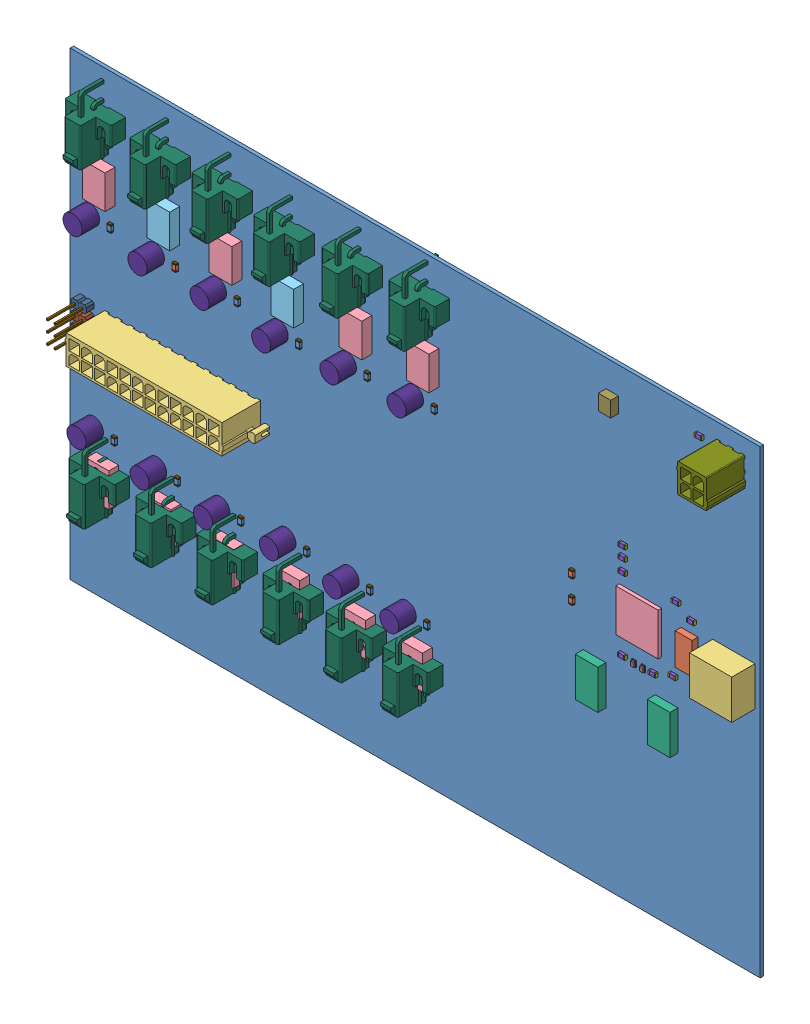
SolidWorks assembly PCBnew, configuration Default. Lengths in mm.
Overall size (228.6 152.53 16.3).
344 component instances, 22 part files, 0 mates.
Components (placement in the parent):
- Board-1: Board [Default] at (0 0 -1.1151) size (228.6 152.53 1.13)
- FTDI-1: FTDI [Default] at origin size (5.6 10.5 1.95)
  - 365783072-1: 365783072 [Default] at (230.632 107.696 0.0627) size (5.6 10.5 1.95)
    - Extruded-1: Extruded [Default] at origin size (5.6 10.5 1.95)
- USB1-1: USB1 [Default] at origin size (14 13 7.7)
  - 365780640-1: 365780640 [Default] at (245.268 108.204 0.0127) size (14 13 7.7)
    - Extruded_1-1: Extruded_1 [Default] at origin size (14 13 7.7)
- U4_Motor_11-1: U4_Motor_11 [Default] at origin size (7.5 11.1 3.3)
  - 365782816-1: 365782816 [Default] at (36.576 145.669 0.1127) size (7.5 11.1 3.3)
    - Extruded_2-1: Extruded_2 [Default] at origin size (7.5 11.1 3.3)
- U4_Motor_10-1: U4_Motor_10 [Default] at origin size (7.5 11.1 3.3)
  - 365782944-1: 365782944 [Default] at (58.039 145.161 0.1127) size (7.5 11.1 3.3)
    - Extruded_3-1: Extruded_3 [Default] at origin size (7.5 11.1 3.3)
- U4_Motor_9-1: U4_Motor_9 [Default] at origin size (7.5 11.1 3.3)
  - 365782816-1: 365782816 [Default] at (78.613 145.542 0.1127) size (7.5 11.1 3.3)
    - Extruded_2-1: Extruded_2 [Default] at origin size (7.5 11.1 3.3)
- U4_Motor_8-1: U4_Motor_8 [Default] at origin size (7.5 11.1 3.3)
  - 365782944-1: 365782944 [Default] at (99.06 143.51 0.1127) size (7.5 11.1 3.3)
    - Extruded_3-1: Extruded_3 [Default] at origin size (7.5 11.1 3.3)
- U4_Motor_7-1: U4_Motor_7 [Default] at origin size (7.5 11.1 3.3)
  - 365782816-1: 365782816 [Default] at (121.666 145.669 0.1127) size (7.5 11.1 3.3)
    - Extruded_2-1: Extruded_2 [Default] at origin size (7.5 11.1 3.3)
- U4_Motor_6-1: U4_Motor_6 [Default] at origin size (7.5 11.1 3.3)
  - 365782816-1: 365782816 [Default] at (143.891 147.32 0.1127) size (7.5 11.1 3.3)
    - Extruded_2-1: Extruded_2 [Default] at origin size (7.5 11.1 3.3)
- U4_Motor_5-1: U4_Motor_5 [Default] at origin size (7.5 11.1 3.3)
  - 365782816-1: 365782816 [Default] at (37.846 60.833 0.1127) size (7.5 11.1 3.3)
    - Extruded_2-1: Extruded_2 [Default] at origin size (7.5 11.1 3.3)
- U4_Motor_4-1: U4_Motor_4 [Default] at origin size (7.5 11.1 3.3)
  - 365782816-1: 365782816 [Default] at (58.42 59.944 0.1127) size (7.5 11.1 3.3)
    - Extruded_2-1: Extruded_2 [Default] at origin size (7.5 11.1 3.3)
- U4_Motor_3-1: U4_Motor_3 [Default] at origin size (7.5 11.1 3.3)
  - 365782816-1: 365782816 [Default] at (79.248 58.928 0.1127) size (7.5 11.1 3.3)
    - Extruded_2-1: Extruded_2 [Default] at origin size (7.5 11.1 3.3)
- U4_Motor_2-1: U4_Motor_2 [Default] at origin size (7.5 11.1 3.3)
  - 365782816-1: 365782816 [Default] at (101.092 60.96 0.1127) size (7.5 11.1 3.3)
    - Extruded_2-1: Extruded_2 [Default] at origin size (7.5 11.1 3.3)
- U4_Motor_1-1: U4_Motor_1 [Default] at origin size (7.5 11.1 3.3)
  - 365782816-1: 365782816 [Default] at (122.936 60.452 0.1127) size (7.5 11.1 3.3)
    - Extruded_2-1: Extruded_2 [Default] at origin size (7.5 11.1 3.3)
- U4_Motor_0-1: U4_Motor_0 [Default] at origin size (7.5 11.1 3.3)
  - 365782816-1: 365782816 [Default] at (141.732 60.452 0.1127) size (7.5 11.1 3.3)
    - Extruded_2-1: Extruded_2 [Default] at origin size (7.5 11.1 3.3)
- U3-1: U3 [Default] at origin size (7.5 13 2.65)
  - 365782560-1: 365782560 [Default] at (199.136 83.82 0.0127) size (7.5 13 2.65)
    - Extruded_4-1: Extruded_4 [Default] at origin size (7.5 13 2.65)
- U2-1: U2 [Default] at origin size (7.5 13 2.65)
  - 365782560-1: 365782560 [Default] at (223.012 82.804 0.0127) size (7.5 13 2.65)
    - Extruded_4-1: Extruded_4 [Default] at origin size (7.5 13 2.65)
- R5-1: R5 [Default] at origin size (2.38 1.3 0.85)
  - 365781408-1: 365781408 [Default] at (235.188 171.196 0.0127) size (0.38 1.3 0.85)
    - Extruded_5-1: Extruded_5 [Default] at origin size (0.38 1.3 0.85)
  - 365781536-1: 365781536 [Default] at (234.188 171.196 0.0127) size (2.2 1.27 0.85)
    - Extruded_6-1: Extruded_6 [Default] at origin size (2.2 1.27 0.85)
  - 365781408-2: 365781408 [Default] at (233.188 171.196 0.0127) size (0.38 1.3 0.85)
    - Extruded_5-1: Extruded_5 [Default] at origin size (0.38 1.3 0.85)
- R4-1: R4 [Default] at origin size (2.38 1.3 0.85)
  - 365781408-1: 365781408 [Default] at (219.948 95.504 0.0127) size (0.38 1.3 0.85)
    - Extruded_5-1: Extruded_5 [Default] at origin size (0.38 1.3 0.85)
  - 365781536-1: 365781536 [Default] at (218.948 95.504 0.0127) size (2.2 1.27 0.85)
    - Extruded_6-1: Extruded_6 [Default] at origin size (2.2 1.27 0.85)
  - 365781408-2: 365781408 [Default] at (217.948 95.504 0.0127) size (0.38 1.3 0.85)
    - Extruded_5-1: Extruded_5 [Default] at origin size (0.38 1.3 0.85)
- R3-1: R3 [Default] at origin size (2.38 1.3 0.85)
  - 365781408-1: 365781408 [Default] at (209.788 95.504 0.0127) size (0.38 1.3 0.85)
    - Extruded_5-1: Extruded_5 [Default] at origin size (0.38 1.3 0.85)
  - 365781536-1: 365781536 [Default] at (208.788 95.504 0.0127) size (2.2 1.27 0.85)
    - Extruded_6-1: Extruded_6 [Default] at origin size (2.2 1.27 0.85)
  - 365781408-2: 365781408 [Default] at (207.788 95.504 0.0127) size (0.38 1.3 0.85)
    - Extruded_5-1: Extruded_5 [Default] at origin size (0.38 1.3 0.85)
- R2-1: R2 [Default] at origin size (2.38 1.3 0.85)
  - 365781408-1: 365781408 [Default] at (226.552 98.044 0.0127) size (0.38 1.3 0.85)
    - Extruded_5-1: Extruded_5 [Default] at origin size (0.38 1.3 0.85)
  - 365781536-1: 365781536 [Default] at (225.552 98.044 0.0127) size (2.2 1.27 0.85)
    - Extruded_6-1: Extruded_6 [Default] at origin size (2.2 1.27 0.85)
  - 365781408-2: 365781408 [Default] at (224.552 98.044 0.0127) size (0.38 1.3 0.85)
    - Extruded_5-1: Extruded_5 [Default] at origin size (0.38 1.3 0.85)
- R1-1: R1 [Default] at origin size (2.38 1.3 0.85)
  - 365781408-1: 365781408 [Default] at (227.568 119.888 0.0127) size (0.38 1.3 0.85)
    - Extruded_5-1: Extruded_5 [Default] at origin size (0.38 1.3 0.85)
  - 365781536-1: 365781536 [Default] at (226.568 119.888 0.0127) size (2.2 1.27 0.85)
    - Extruded_6-1: Extruded_6 [Default] at origin size (2.2 1.27 0.85)
  - 365781408-2: 365781408 [Default] at (225.568 119.888 0.0127) size (0.38 1.3 0.85)
    - Extruded_5-1: Extruded_5 [Default] at origin size (0.38 1.3 0.85)
- P3-1: P3 [Default] at origin size (5.08 2.54 14.73)
  - 365780768-1: 365780768 [Default] at (29.464 107.823 -3.0353) size (0.51 0.51 14.73)
    - Extruded_7-1: Extruded_7 [Default] at origin size (0.51 0.51 14.73)
  - 365780768-2: 365780768 [Default] at (32.004 107.823 -3.0353) size (0.51 0.51 14.73)
    - Extruded_7-1: Extruded_7 [Default] at origin size (0.51 0.51 14.73)
  - 365781152-1: 365781152 [Default] at (29.464 107.823 0.0127) size (2.54 2.54 2.54)
    - Extruded_8-1: Extruded_8 [Default] at origin size (2.54 2.54 2.54)
  - 365781152-2: 365781152 [Default] at (32.004 107.823 0.0127) size (2.54 2.54 2.54)
    - Extruded_8-1: Extruded_8 [Default] at origin size (2.54 2.54 2.54)
- P2-1: P2 [Default] at origin size (5.08 2.54 14.73)
  - 365780768-1: 365780768 [Default] at (32.004 104.267 -3.0353) size (0.51 0.51 14.73)
    - Extruded_7-1: Extruded_7 [Default] at origin size (0.51 0.51 14.73)
  - 365780768-2: 365780768 [Default] at (29.464 104.267 -3.0353) size (0.51 0.51 14.73)
    - Extruded_7-1: Extruded_7 [Default] at origin size (0.51 0.51 14.73)
  - 365781024-1: 365781024 [Default] at (32.004 104.267 0.0127) size (2.54 2.54 2.54)
    - Extruded_9-1: Extruded_9 [Default] at origin size (2.54 2.54 2.54)
  - 365781024-2: 365781024 [Default] at (29.464 104.267 0.0127) size (2.54 2.54 2.54)
    - Extruded_9-1: Extruded_9 [Default] at origin size (2.54 2.54 2.54)
- P1-1: P1 [Default] at origin size (5.08 2.54 14.73)
  - 365780768-1: 365780768 [Default] at (32.004 100.711 -3.0353) size (0.51 0.51 14.73)
    - Extruded_7-1: Extruded_7 [Default] at origin size (0.51 0.51 14.73)
  - 365780768-2: 365780768 [Default] at (29.464 100.711 -3.0353) size (0.51 0.51 14.73)
    - Extruded_7-1: Extruded_7 [Default] at origin size (0.51 0.51 14.73)
  - 365781024-1: 365781024 [Default] at (32.004 100.711 0.0127) size (2.54 2.54 2.54)
    - Extruded_9-1: Extruded_9 [Default] at origin size (2.54 2.54 2.54)
  - 365781024-2: 365781024 [Default] at (29.464 100.711 0.0127) size (2.54 2.54 2.54)
    - Extruded_9-1: Extruded_9 [Default] at origin size (2.54 2.54 2.54)
- NPP-301-1: NPP-301 [Default] at origin size (4.1 5.1 2.55)
  - 365782432-1: 365782432 [Default] at (205.232 166.624 0.2627) size (4.1 5.1 2.55)
    - Extruded_10-1: Extruded_10 [Default] at origin size (4.1 5.1 2.55)
- LED2-1: LED2 [Default] at origin size (1.25 2 0.8)
  - 365782304-1: 365782304 [Default] at (215.392 94.9835 0.0127) size (1.15 1.38 0.8)
    - Extruded_11-1: Extruded_11 [Default] at origin size (1.15 1.38 0.8)
  - 365782176-1: 365782176 [Default] at (215.392 94.996 0.0127) size (1.25 2 0.3)
    - Extruded_12-1: Extruded_12 [Default] at origin size (1.25 2 0.3)
- LED1-1: LED1 [Default] at origin size (1.25 2 0.8)
  - 365782304-1: 365782304 [Default] at (212.344 94.9835 0.0127) size (1.15 1.38 0.8)
    - Extruded_11-1: Extruded_11 [Default] at origin size (1.15 1.38 0.8)
  - 365782176-1: 365782176 [Default] at (212.344 94.996 0.0127) size (1.25 2 0.3)
    - Extruded_12-1: Extruded_12 [Default] at origin size (1.25 2 0.3)
- Con2_Motor_11-1: Con2_Motor_11 [Default] at origin size (15.4 19.9 14.9)
  - 039291027-1: 039291027 [Default] at (36.0931 154.4521 0.0127) x (1 0 0) z (0 -1 0) size (15.4 14.9 19.9)
    - Open CASCADE STEP translator 6.2 19.29.1.1-1: Open CASCADE STEP translator 6.2 19.29.1.1 [Default] at origin size (15.4 14.9 19.9)
- Con2_Motor_10-1: Con2_Motor_10 [Default] at origin size (15.4 19.9 14.9)
  - 039291027-1: 039291027 [Default] at (57.5561 153.9441 0.0127) x (1 0 0) z (0 -1 0) size (15.4 14.9 19.9)
    - Open CASCADE STEP translator 6.2 19.29.1.1-1: Open CASCADE STEP translator 6.2 19.29.1.1 [Default] at origin size (15.4 14.9 19.9)
- Con2_Motor_9-1: Con2_Motor_9 [Default] at origin size (15.4 19.9 14.9)
  - 039291027-1: 039291027 [Default] at (78.1301 154.3251 0.0127) x (1 0 0) z (0 -1 0) size (15.4 14.9 19.9)
    - Open CASCADE STEP translator 6.2 19.29.1.1-1: Open CASCADE STEP translator 6.2 19.29.1.1 [Default] at origin size (15.4 14.9 19.9)
- Con2_Motor_8-1: Con2_Motor_8 [Default] at origin size (15.4 19.9 14.9)
  - 039291027-1: 039291027 [Default] at (98.5771 152.2931 0.0127) x (1 0 0) z (0 -1 0) size (15.4 14.9 19.9)
    - Open CASCADE STEP translator 6.2 19.29.1.1-1: Open CASCADE STEP translator 6.2 19.29.1.1 [Default] at origin size (15.4 14.9 19.9)
- Con2_Motor_7-1: Con2_Motor_7 [Default] at origin size (15.4 19.9 14.9)
  - 039291027-1: 039291027 [Default] at (121.1831 154.4521 0.0127) x (1 0 0) z (0 -1 0) size (15.4 14.9 19.9)
    - Open CASCADE STEP translator 6.2 19.29.1.1-1: Open CASCADE STEP translator 6.2 19.29.1.1 [Default] at origin size (15.4 14.9 19.9)
- Con2_Motor_6-1: Con2_Motor_6 [Default] at origin size (15.4 19.9 14.9)
  - 039291027-1: 039291027 [Default] at (143.4081 156.1031 0.0127) x (1 0 0) z (0 -1 0) size (15.4 14.9 19.9)
    - Open CASCADE STEP translator 6.2 19.29.1.1-1: Open CASCADE STEP translator 6.2 19.29.1.1 [Default] at origin size (15.4 14.9 19.9)
- Con2_Motor_5-1: Con2_Motor_5 [Default] at origin size (15.4 19.9 14.9)
  - 039291027-1: 039291027 [Default] at (37.3631 52.0499 0.0127) x (1 0 0) z (0 -1 0) size (15.4 14.9 19.9)
    - Open CASCADE STEP translator 6.2 19.29.1.1-1: Open CASCADE STEP translator 6.2 19.29.1.1 [Default] at origin size (15.4 14.9 19.9)
- Con2_Motor_4-1: Con2_Motor_4 [Default] at origin size (15.4 19.9 14.9)
  - 039291027-1: 039291027 [Default] at (59.4611 52.0499 0.0127) x (1 0 0) z (0 -1 0) size (15.4 14.9 19.9)
    - Open CASCADE STEP translator 6.2 19.29.1.1-1: Open CASCADE STEP translator 6.2 19.29.1.1 [Default] at origin size (15.4 14.9 19.9)
- Con2_Motor_3-1: Con2_Motor_3 [Default] at origin size (15.4 19.9 14.9)
  - 039291027-1: 039291027 [Default] at (79.7811 51.5419 0.0127) x (1 0 0) z (0 -1 0) size (15.4 14.9 19.9)
    - Open CASCADE STEP translator 6.2 19.29.1.1-1: Open CASCADE STEP translator 6.2 19.29.1.1 [Default] at origin size (15.4 14.9 19.9)
- Con2_Motor_2-1: Con2_Motor_2 [Default] at origin size (15.4 19.9 14.9)
  - 039291027-1: 039291027 [Default] at (101.6251 51.0339 0.0127) x (1 0 0) z (0 -1 0) size (15.4 14.9 19.9)
    - Open CASCADE STEP translator 6.2 19.29.1.1-1: Open CASCADE STEP translator 6.2 19.29.1.1 [Default] at origin size (15.4 14.9 19.9)
- Con2_Motor_1-1: Con2_Motor_1 [Default] at origin size (15.4 19.9 14.9)
  - 039291027-1: 039291027 [Default] at (122.4531 50.5259 0.0127) x (1 0 0) z (0 -1 0) size (15.4 14.9 19.9)
    - Open CASCADE STEP translator 6.2 19.29.1.1-1: Open CASCADE STEP translator 6.2 19.29.1.1 [Default] at origin size (15.4 14.9 19.9)
- Con2_Motor_0-1: Con2_Motor_0 [Default] at origin size (15.4 19.9 14.9)
  - 039291027-1: 039291027 [Default] at (141.2491 50.0179 0.0127) x (1 0 0) z (0 -1 0) size (15.4 14.9 19.9)
    - Open CASCADE STEP translator 6.2 19.29.1.1-1: Open CASCADE STEP translator 6.2 19.29.1.1 [Default] at origin size (15.4 14.9 19.9)
- Con1-1: Con1 [Default] at origin size (10.4 11 16.3)
  - 039281043-1: 039281043 [Default] at (244.214 168.047 0.0127) x (1 0 0) z (0 -1 0) size (10.4 16.3 11)
- C10_Motor_11-1: C10_Motor_11 [Default] at origin size (6.32 6.32 5.8)
  - 365780896-1: 365780896 [Default] at (32.004 133.477 0.0127) size (6.32 6.32 5.8)
    - Extruded_13-1: Extruded_13 [Default] at origin size (6.32 6.32 5.8)
- C10_Motor_10-1: C10_Motor_10 [Default] at origin size (6.32 6.32 5.8)
  - 365780896-1: 365780896 [Default] at (53.467 132.969 0.0127) size (6.32 6.32 5.8)
    - Extruded_13-1: Extruded_13 [Default] at origin size (6.32 6.32 5.8)
- C10_Motor_9-1: C10_Motor_9 [Default] at origin size (6.32 6.32 5.8)
  - 365780896-1: 365780896 [Default] at (74.041 133.35 0.0127) size (6.32 6.32 5.8)
    - Extruded_13-1: Extruded_13 [Default] at origin size (6.32 6.32 5.8)
- C10_Motor_8-1: C10_Motor_8 [Default] at origin size (6.32 6.32 5.8)
  - 365780896-1: 365780896 [Default] at (94.488 131.318 0.0127) size (6.32 6.32 5.8)
    - Extruded_13-1: Extruded_13 [Default] at origin size (6.32 6.32 5.8)
- C10_Motor_7-1: C10_Motor_7 [Default] at origin size (6.32 6.32 5.8)
  - 365780896-1: 365780896 [Default] at (117.094 133.477 0.0127) size (6.32 6.32 5.8)
    - Extruded_13-1: Extruded_13 [Default] at origin size (6.32 6.32 5.8)
- C10_Motor_6-1: C10_Motor_6 [Default] at origin size (6.32 6.32 5.8)
  - 365780896-1: 365780896 [Default] at (139.319 135.128 0.0127) size (6.32 6.32 5.8)
    - Extruded_13-1: Extruded_13 [Default] at origin size (6.32 6.32 5.8)
- C10_Motor_5-1: C10_Motor_5 [Default] at origin size (6.32 6.32 5.8)
  - 365780896-1: 365780896 [Default] at (33.274 73.025 0.0127) size (6.32 6.32 5.8)
    - Extruded_13-1: Extruded_13 [Default] at origin size (6.32 6.32 5.8)
- C10_Motor_4-1: C10_Motor_4 [Default] at origin size (6.32 6.32 5.8)
  - 365780896-1: 365780896 [Default] at (54.229 71.882 0.0127) size (6.32 6.32 5.8)
    - Extruded_13-1: Extruded_13 [Default] at origin size (6.32 6.32 5.8)
- C10_Motor_3-1: C10_Motor_3 [Default] at origin size (6.32 6.32 5.8)
  - 365780896-1: 365780896 [Default] at (75.184 70.993 0.0127) size (6.32 6.32 5.8)
    - Extruded_13-1: Extruded_13 [Default] at origin size (6.32 6.32 5.8)
- C10_Motor_2-1: C10_Motor_2 [Default] at origin size (6.32 6.32 5.8)
  - 365780896-1: 365780896 [Default] at (97.028 73.025 0.0127) size (6.32 6.32 5.8)
    - Extruded_13-1: Extruded_13 [Default] at origin size (6.32 6.32 5.8)
- C10_Motor_1-1: C10_Motor_1 [Default] at origin size (6.32 6.32 5.8)
  - 365780896-1: 365780896 [Default] at (117.983 72.517 0.0127) size (6.32 6.32 5.8)
    - Extruded_13-1: Extruded_13 [Default] at origin size (6.32 6.32 5.8)
- C10_Motor_0-1: C10_Motor_0 [Default] at origin size (6.32 6.32 5.8)
  - 365780896-1: 365780896 [Default] at (136.906 72.009 0.0127) size (6.32 6.32 5.8)
    - Extruded_13-1: Extruded_13 [Default] at origin size (6.32 6.32 5.8)
- C9_Motor_11-1: C9_Motor_11 [Default] at origin size (1.3 2.38 0.85)
  - 365781792-1: 365781792 [Default] at (39.116 134.477 0.0127) size (1.3 0.38 0.85)
    - Extruded_14-1: Extruded_14 [Default] at origin size (1.3 0.38 0.85)
  - 365782048-1: 365782048 [Default] at (39.116 133.477 0.0127) size (1.27 2.2 0.85)
    - Extruded_15-1: Extruded_15 [Default] at origin size (1.27 2.2 0.85)
  - 365781792-2: 365781792 [Default] at (39.116 132.477 0.0127) size (1.3 0.38 0.85)
    - Extruded_14-1: Extruded_14 [Default] at origin size (1.3 0.38 0.85)
- C9_Motor_10-1: C9_Motor_10 [Default] at origin size (1.3 2.38 0.85)
  - 365781792-1: 365781792 [Default] at (60.579 133.969 0.0127) size (1.3 0.38 0.85)
    - Extruded_14-1: Extruded_14 [Default] at origin size (1.3 0.38 0.85)
  - 365781920-1: 365781920 [Default] at (60.579 132.969 0.0127) size (1.27 2.2 0.85)
    - Extruded_16-1: Extruded_16 [Default] at origin size (1.27 2.2 0.85)
  - 365781792-2: 365781792 [Default] at (60.579 131.969 0.0127) size (1.3 0.38 0.85)
    - Extruded_14-1: Extruded_14 [Default] at origin size (1.3 0.38 0.85)
- C9_Motor_9-1: C9_Motor_9 [Default] at origin size (1.3 2.38 0.85)
  - 365781792-1: 365781792 [Default] at (81.153 134.35 0.0127) size (1.3 0.38 0.85)
    - Extruded_14-1: Extruded_14 [Default] at origin size (1.3 0.38 0.85)
  - 365782048-1: 365782048 [Default] at (81.153 133.35 0.0127) size (1.27 2.2 0.85)
    - Extruded_15-1: Extruded_15 [Default] at origin size (1.27 2.2 0.85)
  - 365781792-2: 365781792 [Default] at (81.153 132.35 0.0127) size (1.3 0.38 0.85)
    - Extruded_14-1: Extruded_14 [Default] at origin size (1.3 0.38 0.85)
- C9_Motor_8-1: C9_Motor_8 [Default] at origin size (1.3 2.38 0.85)
  - 365781792-1: 365781792 [Default] at (101.6 132.318 0.0127) size (1.3 0.38 0.85)
    - Extruded_14-1: Extruded_14 [Default] at origin size (1.3 0.38 0.85)
  - 365782048-1: 365782048 [Default] at (101.6 131.318 0.0127) size (1.27 2.2 0.85)
    - Extruded_15-1: Extruded_15 [Default] at origin size (1.27 2.2 0.85)
  - 365781792-2: 365781792 [Default] at (101.6 130.318 0.0127) size (1.3 0.38 0.85)
    - Extruded_14-1: Extruded_14 [Default] at origin size (1.3 0.38 0.85)
- C9_Motor_7-1: C9_Motor_7 [Default] at origin size (1.3 2.38 0.85)
  - 365781792-1: 365781792 [Default] at (124.206 134.477 0.0127) size (1.3 0.38 0.85)
    - Extruded_14-1: Extruded_14 [Default] at origin size (1.3 0.38 0.85)
  - 365782048-1: 365782048 [Default] at (124.206 133.477 0.0127) size (1.27 2.2 0.85)
    - Extruded_15-1: Extruded_15 [Default] at origin size (1.27 2.2 0.85)
  - 365781792-2: 365781792 [Default] at (124.206 132.477 0.0127) size (1.3 0.38 0.85)
    - Extruded_14-1: Extruded_14 [Default] at origin size (1.3 0.38 0.85)
- C9_Motor_6-1: C9_Motor_6 [Default] at origin size (1.3 2.38 0.85)
  - 365781792-1: 365781792 [Default] at (146.431 136.128 0.0127) size (1.3 0.38 0.85)
    - Extruded_14-1: Extruded_14 [Default] at origin size (1.3 0.38 0.85)
  - 365782048-1: 365782048 [Default] at (146.431 135.128 0.0127) size (1.27 2.2 0.85)
    - Extruded_15-1: Extruded_15 [Default] at origin size (1.27 2.2 0.85)
  - 365781792-2: 365781792 [Default] at (146.431 134.128 0.0127) size (1.3 0.38 0.85)
    - Extruded_14-1: Extruded_14 [Default] at origin size (1.3 0.38 0.85)
- C9_Motor_5-1: C9_Motor_5 [Default] at origin size (1.3 2.38 0.85)
  - 365781792-1: 365781792 [Default] at (40.386 72.025 0.0127) size (1.3 0.38 0.85)
    - Extruded_14-1: Extruded_14 [Default] at origin size (1.3 0.38 0.85)
  - 365782048-1: 365782048 [Default] at (40.386 73.025 0.0127) size (1.27 2.2 0.85)
    - Extruded_15-1: Extruded_15 [Default] at origin size (1.27 2.2 0.85)
  - 365781792-2: 365781792 [Default] at (40.386 74.025 0.0127) size (1.3 0.38 0.85)
    - Extruded_14-1: Extruded_14 [Default] at origin size (1.3 0.38 0.85)
- C9_Motor_4-1: C9_Motor_4 [Default] at origin size (1.3 2.38 0.85)
  - 365781792-1: 365781792 [Default] at (61.341 70.882 0.0127) size (1.3 0.38 0.85)
    - Extruded_14-1: Extruded_14 [Default] at origin size (1.3 0.38 0.85)
  - 365782048-1: 365782048 [Default] at (61.341 71.882 0.0127) size (1.27 2.2 0.85)
    - Extruded_15-1: Extruded_15 [Default] at origin size (1.27 2.2 0.85)
  - 365781792-2: 365781792 [Default] at (61.341 72.882 0.0127) size (1.3 0.38 0.85)
    - Extruded_14-1: Extruded_14 [Default] at origin size (1.3 0.38 0.85)
- C9_Motor_3-1: C9_Motor_3 [Default] at origin size (1.3 2.38 0.85)
  - 365781792-1: 365781792 [Default] at (82.296 69.993 0.0127) size (1.3 0.38 0.85)
    - Extruded_14-1: Extruded_14 [Default] at origin size (1.3 0.38 0.85)
  - 365782048-1: 365782048 [Default] at (82.296 70.993 0.0127) size (1.27 2.2 0.85)
    - Extruded_15-1: Extruded_15 [Default] at origin size (1.27 2.2 0.85)
  - 365781792-2: 365781792 [Default] at (82.296 71.993 0.0127) size (1.3 0.38 0.85)
    - Extruded_14-1: Extruded_14 [Default] at origin size (1.3 0.38 0.85)
- C9_Motor_2-1: C9_Motor_2 [Default] at origin size (1.3 2.38 0.85)
  - 365781792-1: 365781792 [Default] at (104.14 72.025 0.0127) size (1.3 0.38 0.85)
    - Extruded_14-1: Extruded_14 [Default] at origin size (1.3 0.38 0.85)
  - 365782048-1: 365782048 [Default] at (104.14 73.025 0.0127) size (1.27 2.2 0.85)
    - Extruded_15-1: Extruded_15 [Default] at origin size (1.27 2.2 0.85)
  - 365781792-2: 365781792 [Default] at (104.14 74.025 0.0127) size (1.3 0.38 0.85)
    - Extruded_14-1: Extruded_14 [Default] at origin size (1.3 0.38 0.85)
- C9_Motor_1-1: C9_Motor_1 [Default] at origin size (1.3 2.38 0.85)
  - 365781792-1: 365781792 [Default] at (125.095 71.517 0.0127) size (1.3 0.38 0.85)
    - Extruded_14-1: Extruded_14 [Default] at origin size (1.3 0.38 0.85)
  - 365782048-1: 365782048 [Default] at (125.095 72.517 0.0127) size (1.27 2.2 0.85)
    - Extruded_15-1: Extruded_15 [Default] at origin size (1.27 2.2 0.85)
  - 365781792-2: 365781792 [Default] at (125.095 73.517 0.0127) size (1.3 0.38 0.85)
    - Extruded_14-1: Extruded_14 [Default] at origin size (1.3 0.38 0.85)
- C9_Motor_0-1: C9_Motor_0 [Default] at origin size (1.3 2.38 0.85)
  - 365781792-1: 365781792 [Default] at (144.018 71.009 0.0127) size (1.3 0.38 0.85)
    - Extruded_14-1: Extruded_14 [Default] at origin size (1.3 0.38 0.85)
  - 365782048-1: 365782048 [Default] at (144.018 72.009 0.0127) size (1.27 2.2 0.85)
    - Extruded_15-1: Extruded_15 [Default] at origin size (1.27 2.2 0.85)
  - 365781792-2: 365781792 [Default] at (144.018 73.009 0.0127) size (1.3 0.38 0.85)
    - Extruded_14-1: Extruded_14 [Default] at origin size (1.3 0.38 0.85)
- C8-1: C8 [Default] at origin size (1.3 2.38 0.85)
  - 365781792-1: 365781792 [Default] at (192.024 111.744 0.0127) size (1.3 0.38 0.85)
    - Extruded_14-1: Extruded_14 [Default] at origin size (1.3 0.38 0.85)
  - 365781920-1: 365781920 [Default] at (192.024 110.744 0.0127) size (1.27 2.2 0.85)
    - Extruded_16-1: Extruded_16 [Default] at origin size (1.27 2.2 0.85)
  - 365781792-2: 365781792 [Default] at (192.024 109.744 0.0127) size (1.3 0.38 0.85)
    - Extruded_14-1: Extruded_14 [Default] at origin size (1.3 0.38 0.85)
- C7-1: C7 [Default] at origin size (2.38 1.3 0.85)
  - 365781408-1: 365781408 [Default] at (240.776 157.988 0.0127) size (0.38 1.3 0.85)
    - Extruded_5-1: Extruded_5 [Default] at origin size (0.38 1.3 0.85)
  - 365781536-1: 365781536 [Default] at (239.776 157.988 0.0127) size (2.2 1.27 0.85)
    - Extruded_6-1: Extruded_6 [Default] at origin size (2.2 1.27 0.85)
  - 365781408-2: 365781408 [Default] at (238.776 157.988 0.0127) size (0.38 1.3 0.85)
    - Extruded_5-1: Extruded_5 [Default] at origin size (0.38 1.3 0.85)
- C6-1: C6 [Default] at origin size (1.3 2.38 0.85)
  - 365781792-1: 365781792 [Default] at (192.024 104.124 0.0127) size (1.3 0.38 0.85)
    - Extruded_14-1: Extruded_14 [Default] at origin size (1.3 0.38 0.85)
  - 365781920-1: 365781920 [Default] at (192.024 103.124 0.0127) size (1.27 2.2 0.85)
    - Extruded_16-1: Extruded_16 [Default] at origin size (1.27 2.2 0.85)
  - 365781792-2: 365781792 [Default] at (192.024 102.124 0.0127) size (1.3 0.38 0.85)
    - Extruded_14-1: Extruded_14 [Default] at origin size (1.3 0.38 0.85)
- C5-1: C5 [Default] at origin size (2.38 1.3 0.85)
  - 365781408-1: 365781408 [Default] at (237.22 98.044 0.0127) size (0.38 1.3 0.85)
    - Extruded_5-1: Extruded_5 [Default] at origin size (0.38 1.3 0.85)
  - 365781536-1: 365781536 [Default] at (236.22 98.044 0.0127) size (2.2 1.27 0.85)
    - Extruded_6-1: Extruded_6 [Default] at origin size (2.2 1.27 0.85)
  - 365781408-2: 365781408 [Default] at (235.22 98.044 0.0127) size (0.38 1.3 0.85)
    - Extruded_5-1: Extruded_5 [Default] at origin size (0.38 1.3 0.85)
- C4-1: C4 [Default] at origin size (2.38 1.3 0.85)
  - 365781408-1: 365781408 [Default] at (232.648 116.84 0.0127) size (0.38 1.3 0.85)
    - Extruded_5-1: Extruded_5 [Default] at origin size (0.38 1.3 0.85)
  - 365781536-1: 365781536 [Default] at (231.648 116.84 0.0127) size (2.2 1.27 0.85)
    - Extruded_6-1: Extruded_6 [Default] at origin size (2.2 1.27 0.85)
  - 365781408-2: 365781408 [Default] at (230.648 116.84 0.0127) size (0.38 1.3 0.85)
    - Extruded_5-1: Extruded_5 [Default] at origin size (0.38 1.3 0.85)
- C3-1: C3 [Default] at origin size (2.38 1.3 0.85)
  - 365781408-1: 365781408 [Default] at (209.915 119.634 0.0127) size (0.38 1.3 0.85)
    - Extruded_5-1: Extruded_5 [Default] at origin size (0.38 1.3 0.85)
  - 365781536-1: 365781536 [Default] at (208.915 119.634 0.0127) size (2.2 1.27 0.85)
    - Extruded_6-1: Extruded_6 [Default] at origin size (2.2 1.27 0.85)
  - 365781408-2: 365781408 [Default] at (207.915 119.634 0.0127) size (0.38 1.3 0.85)
    - Extruded_5-1: Extruded_5 [Default] at origin size (0.38 1.3 0.85)
- C2-1: C2 [Default] at origin size (2.38 1.3 0.85)
  - 365781408-1: 365781408 [Default] at (209.915 123.698 0.0127) size (0.38 1.3 0.85)
    - Extruded_5-1: Extruded_5 [Default] at origin size (0.38 1.3 0.85)
  - 365781536-1: 365781536 [Default] at (208.915 123.698 0.0127) size (2.2 1.27 0.85)
    - Extruded_6-1: Extruded_6 [Default] at origin size (2.2 1.27 0.85)
  - 365781408-2: 365781408 [Default] at (207.915 123.698 0.0127) size (0.38 1.3 0.85)
    - Extruded_5-1: Extruded_5 [Default] at origin size (0.38 1.3 0.85)
- C1-1: C1 [Default] at origin size (2.38 1.3 0.85)
  - 365781408-1: 365781408 [Default] at (209.915 127.254 0.0127) size (0.38 1.3 0.85)
    - Extruded_5-1: Extruded_5 [Default] at origin size (0.38 1.3 0.85)
  - 365781536-1: 365781536 [Default] at (208.915 127.254 0.0127) size (2.2 1.27 0.85)
    - Extruded_6-1: Extruded_6 [Default] at origin size (2.2 1.27 0.85)
  - 365781408-2: 365781408 [Default] at (207.915 127.254 0.0127) size (0.38 1.3 0.85)
    - Extruded_5-1: Extruded_5 [Default] at origin size (0.38 1.3 0.85)
- ATX1-1: ATX1 [Default] at origin size (57.6 11.1 16.3)
  - 039299244-1: 039299244 [Default] at (62.6872 103.5564 0.0127) x (-1 0 0) z (0 1 0) size (57.6 16.3 11.1)
    - Open CASCADE STEP translator 6.2 19.74.1.1-1: Open CASCADE STEP translator 6.2 19.74.1.1 [Default] at origin size (57.6 16.3 11.1)
- Imported-1: Imported [Default] at origin size (14 14 1.15)
  - 365781280-1: 365781280 [Default] at (214.376 108.204 0.0627) size (14 14 1.15)
    - Extruded_17-1: Extruded_17 [Default] at origin size (14 14 1.15)
